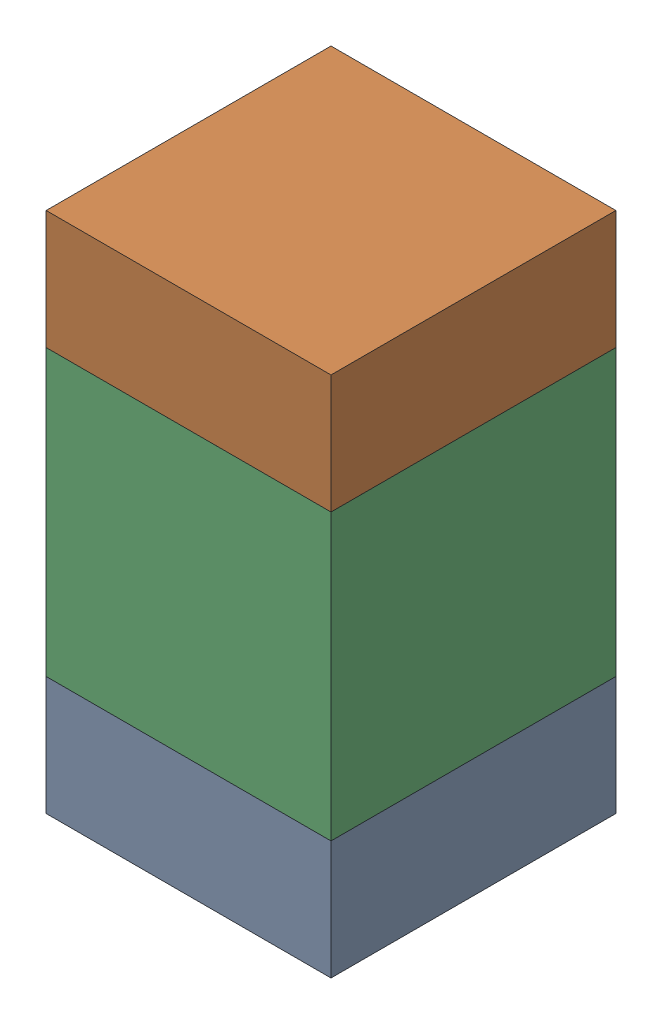
SolidWorks assembly C103_2PCB, configuration Default. Lengths in mm.
Overall size (0.6 1.1 0.6).
6 component instances, 2 part files, 0 mates.
Components (placement in the parent):
- 854785296-1: 854785296 [Default] at (104.1 83.875 0) size (0.6 0.25 0.6)
  - Extruded_10-1: Extruded_10 [Default] at origin size (0.6 0.25 0.6)
- 854785296-2: 854785296 [Default] at (104.1 84.725 0) size (0.6 0.25 0.6)
  - Extruded_10-1: Extruded_10 [Default] at origin size (0.6 0.25 0.6)
- 761606048-1: 761606048 [Default] at (104.1 84.3 0) size (0.6 0.6 0.6)
  - Extruded_9-1: Extruded_9 [Default] at origin size (0.6 0.6 0.6)
